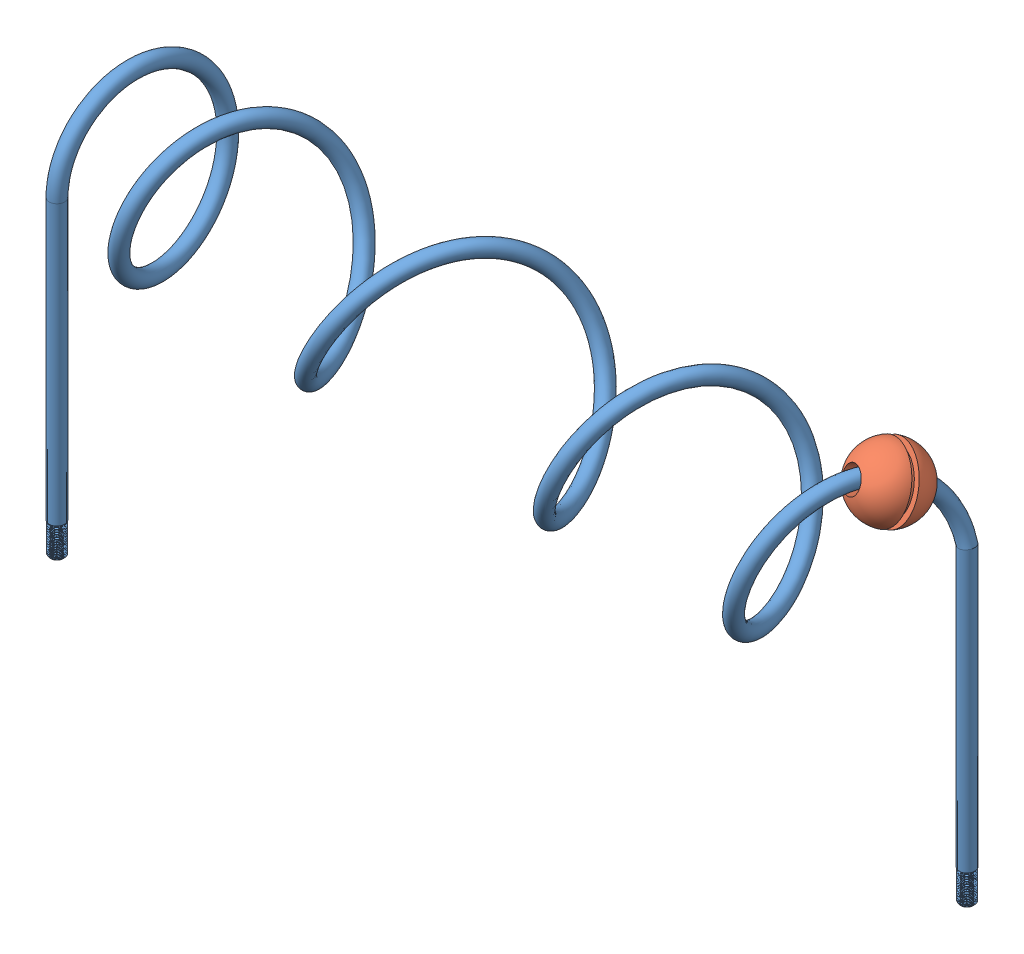
SolidWorks assembly sestava_spirala_kulicka_01_upr, configuration Výchozí. Lengths in mm.
Overall size (251.79 137.1 55.52).
2 component instances, 2 part files, 2 mates.
Components (placement in the parent):
- krivka_spirala_01_cela_krivka_upr-1: krivka_spirala_01_cela_krivka_upr [Výchozí] at origin size (248.68 127.68 55.52)
- kulicka_01-1: kulicka_01 [Výchozí] at (238.1465 42.4009 -18.3528) x (0.084164 -0.914365 0.396048) z (-0.952734 -0.19028 -0.236838) size (21.91 20.49 21.91)
Mates (geometry in assembly coordinates):
- Vazba Trajektorie3: path: point of kulicka_01-1; curve of krivka_spirala_01_cela_krivka_upr-1
- Vazba Trajektorie4: path: point of kulicka_01-1; curve of krivka_spirala_01_cela_krivka_upr-1
